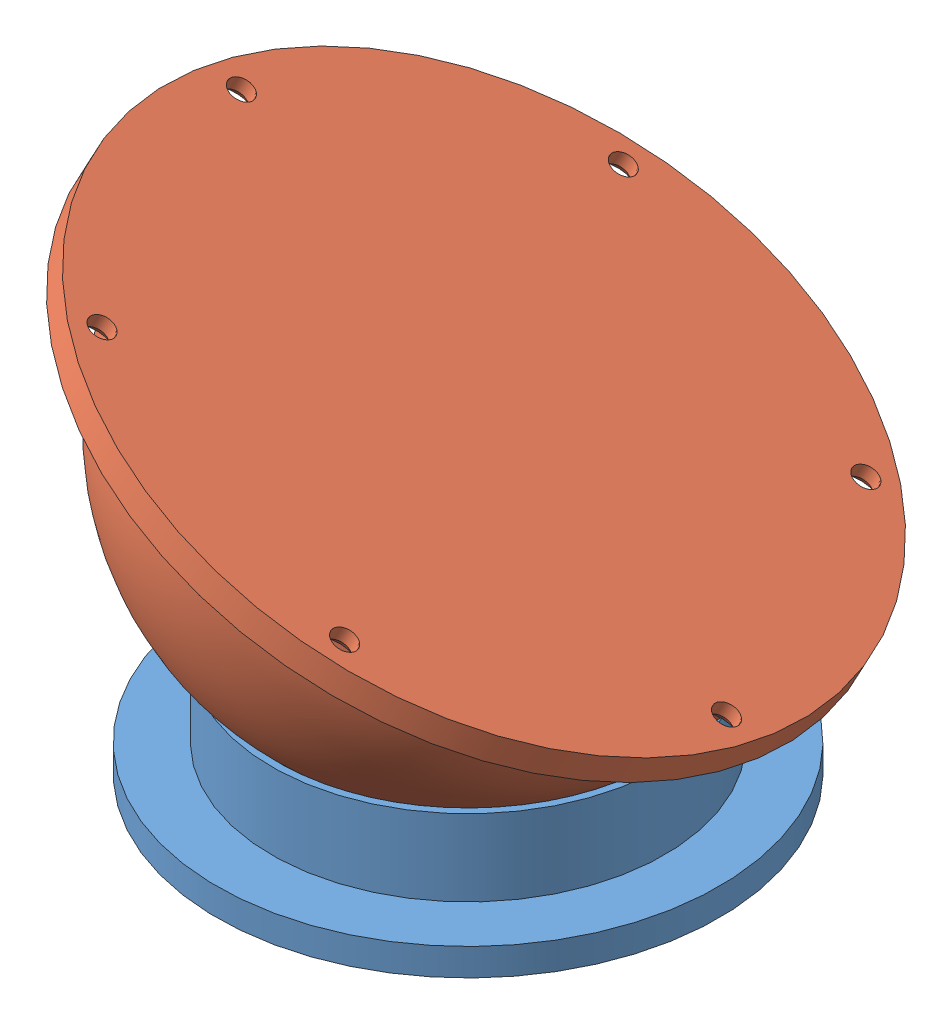
SolidWorks assembly Сборка, configuration По умолчанию. Lengths in mm.
Overall size (173.17 122.66 174.8).
2 component instances, 2 part files, 1 mates.
Components (placement in the parent):
- чашка-1: чашка [По умолчанию] at origin size (92 19 92)
- шарик-1: шарик [По умолчанию] x (0.779063 -0.237072 0.580394) z (0.47812 -0.374157 -0.794612) size (120 55 120)
Mates (geometry in assembly coordinates):
- Концентрический1: concentric: sphere of чашка-1; sphere of шарик-1
